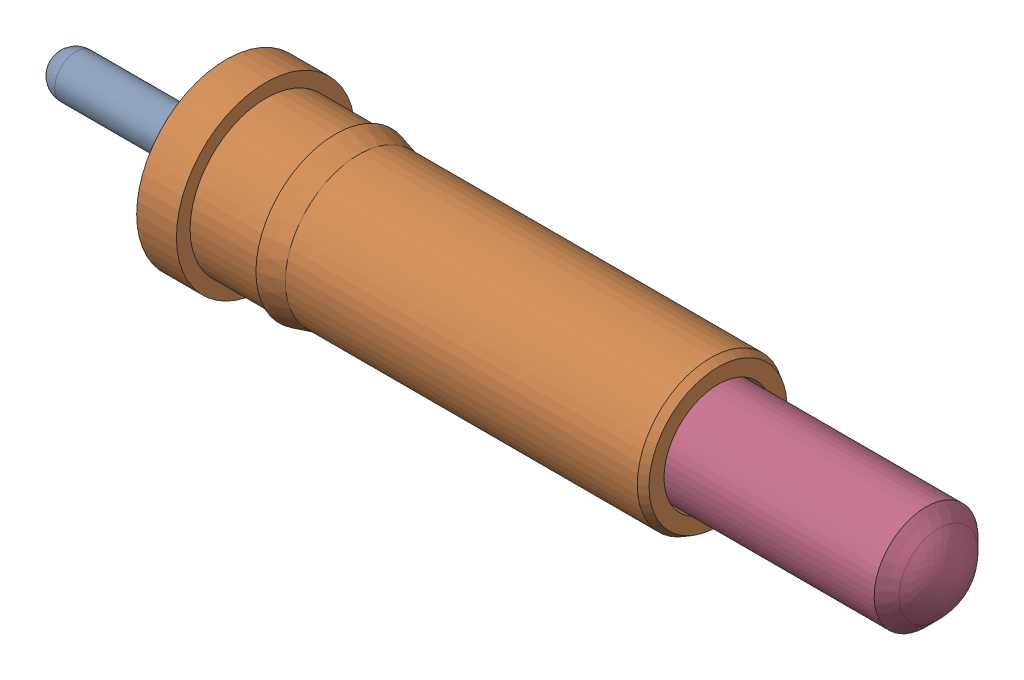
SolidWorks assembly mill-max-0908-2-15-20-75-14-11-0_3, configuration Default. Lengths in mm.
Overall size (9.22 1.83 1.83).
4 component instances, 4 part files, 0 mates.
Components (placement in the parent):
- mill-max-0908-2-15-20-75-14-11-0_0963-0_0963-0-00-20-00-00-13-0_1-1: mill-max-0908-2-15-20-75-14-11-0_0963-0_0963-0-00-20-00-00-13-0_1 [Default] at (0.1795 -0.8235 -1.1087) size (4.04 1.31 1.31)
- mill-max-0908-2-15-20-75-14-11-0_0954-0_0954-0-00-20-00-00-13-0_1-1: mill-max-0908-2-15-20-75-14-11-0_0954-0_0954-0-00-20-00-00-13-0_1 [Default] at (1.9321 -0.8235 -1.1087) size (5.03 1.83 1.83)
- mill-max-0908-2-15-20-75-14-11-0_SPRING_0975-0-00-00-75-14-45-0_1-1: mill-max-0908-2-15-20-75-14-11-0_SPRING_0975-0-00-00-75-14-45-0_1 [Default] at (5.5978 -0.8235 -1.1087) x (0 -0.998082 0.061903) z (-1 0 0) size (0.8 0.8 3.43)
- mill-max-0908-2-15-20-75-14-11-0_0918-X_0918-7-00-20-00-00-13-0_1-1: mill-max-0908-2-15-20-75-14-11-0_0918-X_0918-7-00-20-00-00-13-0_1 [Default] at (3.9133 -0.8235 -1.1087) x (1 0 0) z (0 0.540629 0.841261) size (5.49 1.25 1.25)
